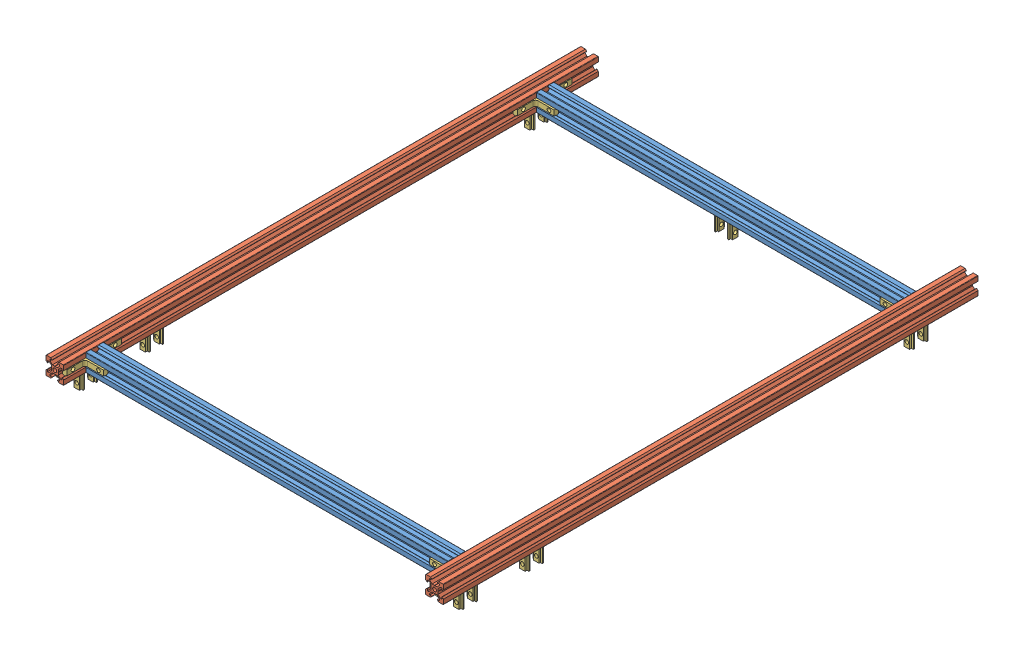
SolidWorks assembly corexy_frame_assembly, configuration Default. Lengths in mm.
Overall size (449 40.45 604).
26 component instances, 3 part files, 0 mates.
Components (placement in the parent):
- 409mm_2020_tslot_extrusion-1: 409mm_2020_tslot_extrusion [Default] at origin size (409 20 20)
- 409mm_2020_tslot_extrusion-2: 409mm_2020_tslot_extrusion [Default] at (0 0 509) size (409 20 20)
- 604mm_2020_tslot_extrusion-1: 604mm_2020_tslot_extrusion [Default] at origin size (20 20 604)
- 604mm_2020_tslot_extrusion-2: 604mm_2020_tslot_extrusion [Default] at (429 0 0) size (20 20 604)
- inside_hidden_corner_bracket-1: inside_hidden_corner_bracket [Default] at (4.45 0 -29.6) x (0 0 1) z (0 1 0) size (25.5 26 10.4)
- inside_hidden_corner_bracket-2: inside_hidden_corner_bracket [Default] at (4.45 0 -40.4) x (0 0 -1) z (0 -1 0) size (25.5 26 10.4)
- inside_hidden_corner_bracket-3: inside_hidden_corner_bracket [Default] at (4.45 0 -549.4) x (0 0 -1) z (0 -1 0) size (25.5 26 10.4)
- inside_hidden_corner_bracket-4: inside_hidden_corner_bracket [Default] at (4.45 0 -538.6) x (0 0 1) z (0 1 0) size (25.5 26 10.4)
- inside_hidden_corner_bracket-5: inside_hidden_corner_bracket [Default] at (424.55 0 -538.6) x (0 0 1) z (0 -1 0) size (25.5 26 10.4)
- inside_hidden_corner_bracket-6: inside_hidden_corner_bracket [Default] at (424.55 0 -549.4) x (0 0 -1) z (0 1 0) size (25.5 26 10.4)
- inside_hidden_corner_bracket-7: inside_hidden_corner_bracket [Default] at (424.55 0 -29.6) x (0 0 1) z (0 -1 0) size (25.5 26 10.4)
- inside_hidden_corner_bracket-8: inside_hidden_corner_bracket [Default] at (424.55 0 -40.4) x (0 0 -1) z (0 1 0) size (25.5 26 10.4)
- inside_hidden_corner_bracket-9: inside_hidden_corner_bracket [Default] at (209.1 -4.45 -544) x (-1 0 0) z (0 0 1) size (25.5 26 10.4)
- inside_hidden_corner_bracket-10: inside_hidden_corner_bracket [Default] at (219.9 -4.45 -544) x (1 0 0) z (0 0 -1) size (25.5 26 10.4)
- inside_hidden_corner_bracket-11: inside_hidden_corner_bracket [Default] at (0 -4.45 -538.6) x (0 0 1) z (1 0 0) size (25.5 26 10.4)
- inside_hidden_corner_bracket-12: inside_hidden_corner_bracket [Default] at (0 -4.45 -549.4) x (0 0 -1) z (-1 0 0) size (25.5 26 10.4)
- inside_hidden_corner_bracket-13: inside_hidden_corner_bracket [Default] at (0 -4.45 -104.225) x (0 0 1) z (1 0 0) size (25.5 26 10.4)
- inside_hidden_corner_bracket-14: inside_hidden_corner_bracket [Default] at (0 -4.45 -115.025) x (0 0 -1) z (-1 0 0) size (25.5 26 10.4)
- inside_hidden_corner_bracket-15: inside_hidden_corner_bracket [Default] at (0 -4.45 -29.6) x (0 0 1) z (1 0 0) size (25.5 26 10.4)
- inside_hidden_corner_bracket-16: inside_hidden_corner_bracket [Default] at (0 -4.45 -40.4) x (0 0 -1) z (-1 0 0) size (25.5 26 10.4)
- inside_hidden_corner_bracket-17: inside_hidden_corner_bracket [Default] at (429 -4.45 -549.4) x (0 0 -1) z (-1 0 0) size (25.5 26 10.4)
- inside_hidden_corner_bracket-18: inside_hidden_corner_bracket [Default] at (429 -4.45 -538.6) x (0 0 1) z (1 0 0) size (25.5 26 10.4)
- inside_hidden_corner_bracket-19: inside_hidden_corner_bracket [Default] at (429 -4.45 -104.225) x (0 0 1) z (1 0 0) size (25.5 26 10.4)
- inside_hidden_corner_bracket-20: inside_hidden_corner_bracket [Default] at (429 -4.45 -115.025) x (0 0 -1) z (-1 0 0) size (25.5 26 10.4)
- inside_hidden_corner_bracket-21: inside_hidden_corner_bracket [Default] at (429 -4.45 -29.6) x (0 0 1) z (1 0 0) size (25.5 26 10.4)
- inside_hidden_corner_bracket-22: inside_hidden_corner_bracket [Default] at (429 -4.45 -40.4) x (0 0 -1) z (-1 0 0) size (25.5 26 10.4)
